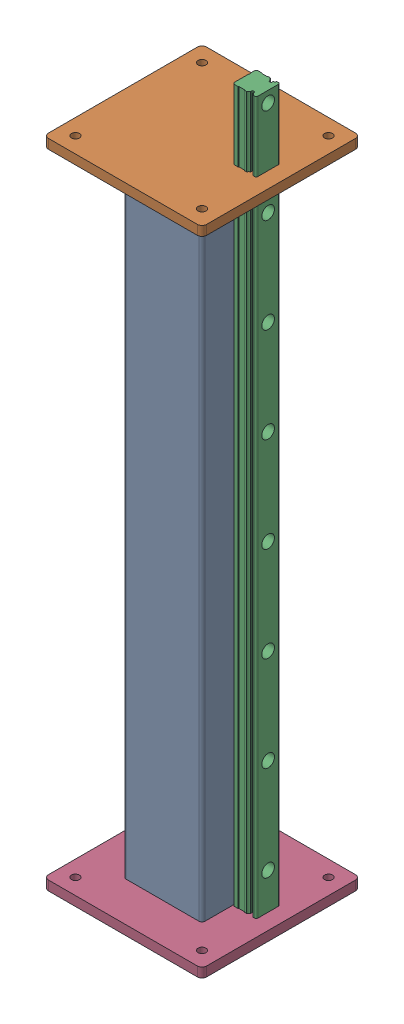
SolidWorks assembly X, configuration Default. Lengths in mm.
Overall size (100 456 100).
4 component instances, 3 part files, 7 mates.
Components (placement in the parent):
- hop 50x50x3xL480-1: hop 50x50x3xL480 [Default] at (195.5294 13.7996 369.3686) size (50 400 50)
- bich3-2: bich3 [Default] at (180.5294 413.7996 304.3686) size (100 6 100)
- ray truot 450-1-1: ray truot 450-1 [Default] at (245.5294 456.7996 342.5686) x (0 -1 0) z (0 0 1) size (450 15.23 15)
- bich3-4: bich3 [Default] at (180.5294 13.7996 384.3686) x (1 0 0) z (0 0 -1) size (100 6 100)
Mates (geometry in assembly coordinates):
- Coincident4: coincident anti-aligned: plane of hop 50x50x3xL480-1 through (245.5294 413.7996 367.3686) normal (1 0 0); plane of ray truot 450-1-1 through (245.5294 463.7996 349.0686) normal (-1 0 0)
- Parallel1: parallel aligned: line of hop 50x50x3xL480-1 through (245.5294 413.7996 321.3686) axis (0 -1 0); line of ray truot 450-1-1 through (249.0294 463.7996 335.0686) axis (0 -1 0)
- Coincident5: coincident aligned: plane of hop 50x50x3xL480-1 through (197.5294 13.7996 367.3686) normal (0 -1 0); plane of ray truot 450-1-1 through (245.5294 13.7996 350.0686) normal (0 -1 0)
- Coincident6: coincident: point of hop 50x50x3xL480-1; unknown of ray truot 450-1-1
- Coincident7: coincident anti-aligned: plane of hop 50x50x3xL480-1 through (197.5294 413.7996 367.3686) normal (0 1 0); plane of bich3-2 through (180.5294 413.7996 304.3686) normal (0 -1 0)
- Distance3: distance = 25 mm: line of bich3-2 through (170.5294 413.7996 297.3686) axis (0 0 1); line of hop 50x50x3xL480-1 through (195.5294 413.7996 321.3686) axis (0 0 1)
- Distance4: distance = 25 mm: line of hop 50x50x3xL480-1 through (243.5294 413.7996 319.3686) axis (-1 0 0); line of bich3-2 through (267.5294 413.7996 294.3686) axis (-1 0 0)
